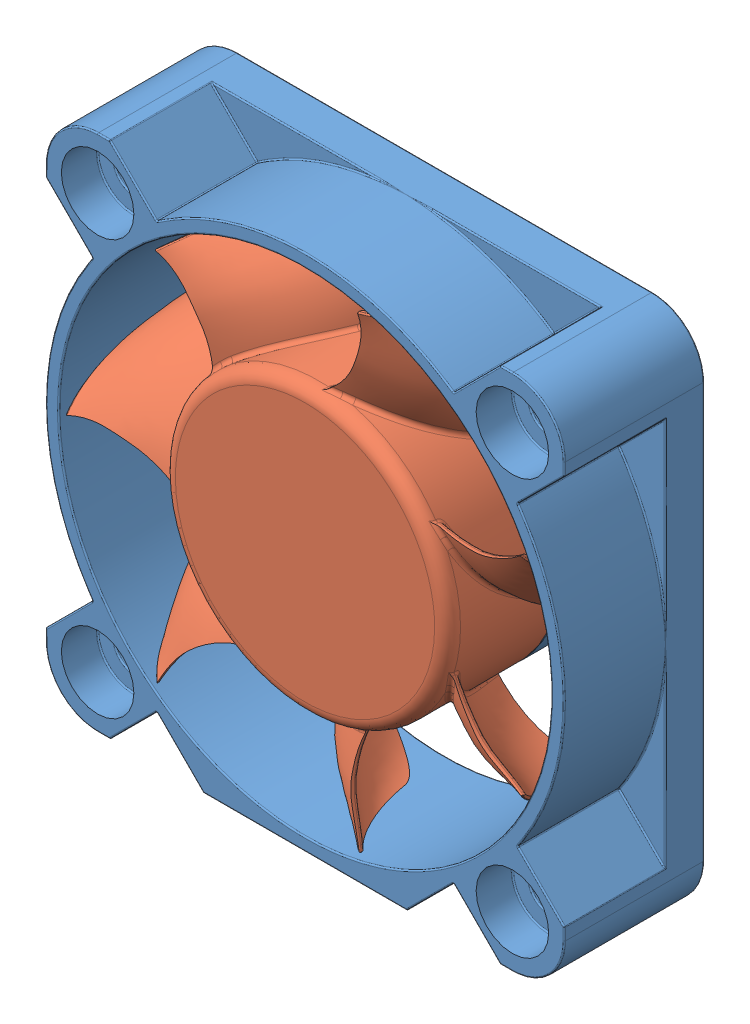
SolidWorks assembly CPU - -KF0410-01, configuration По умолчанию. Lengths in mm.
Overall size (40.01 40.11 10.82).
2 component instances, 2 part files, 2 mates.
Components (placement in the parent):
- CPU - -KF0410-01-PLASTIC CASING-1: CPU - -KF0410-01-PLASTIC CASING [По умолчанию] at (0.9289 7.0036 0) size (40.01 40.11 10.81)
- CPU - -KF0410-01- PLASTIC ROTOR-1: CPU - -KF0410-01- PLASTIC ROTOR [По умолчанию] at (0.9289 7.0036 -1) size (37.4 37 9.12)
Mates (geometry in assembly coordinates):
- Concentric1: concentric: cylinder of CPU - -KF0410-01-PLASTIC CASING-1 through (0.9289 7.0036 7.7) axis (0 0 -1) radius 19; cylinder of CPU - -KF0410-01- PLASTIC ROTOR-1 through (0.9289 7.0036 -1) axis (0 0 1) radius 11
- Coincident1: coincident anti-aligned: plane of CPU - -KF0410-01-PLASTIC CASING-1 through (-0.2527 6.56 -1) normal (0 0 1); plane of CPU - -KF0410-01- PLASTIC ROTOR-1 through (0.9289 7.0036 -1) normal (0 0 -1)
